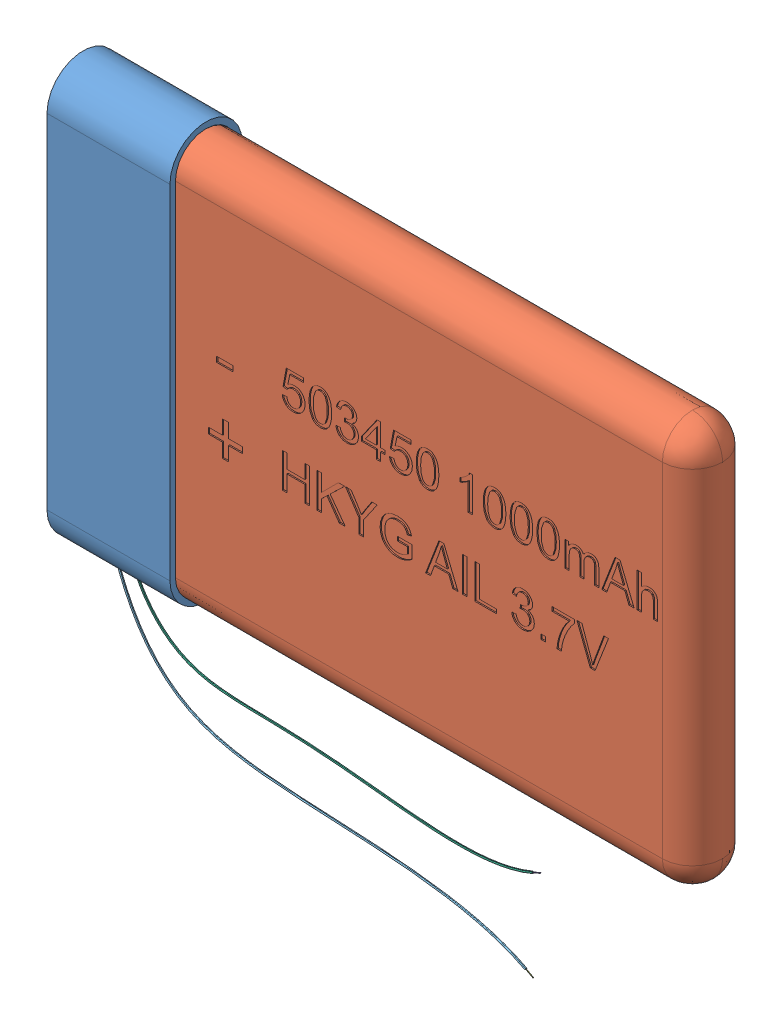
SolidWorks assembly Bateria LiPo 3.7V 1000mA 503450 v23, configuration Predeterminado. Lengths in mm.
Overall size (40.92 46.82 23.16).
9 component instances, 8 part files, 0 mates.
Components (placement in the parent):
- parte de la pila_lipo v4-1: parte de la pila_lipo v4 [Predeterminado] at (-27.4003 0 2.4569) x (0 1 0) z (-1 0 0) size (34.5 6 10.2)
- COMPOUND007-1: COMPOUND007 [Predeterminado] at origin size (40.92 42.22 21.59)
  - COMPOUND-1: COMPOUND [Predeterminado] at origin size (5.9 5.4 4.15)
  - COMPOUND001-1: COMPOUND001 [Predeterminado] at origin size (3 9 0.2)
  - COMPOUND002-1: COMPOUND002 [Predeterminado] at origin size (3 9 0.2)
  - COMPOUND003-1: COMPOUND003 [Predeterminado] at origin size (34.86 31.57 0.38)
  - COMPOUND004-1: COMPOUND004 [Predeterminado] at origin size (34.64 21.24 0.38)
  - COMPOUND005-1: COMPOUND005 [Predeterminado] at origin size (0.64 0.37 0.05)
  - COMPOUND006-1: COMPOUND006 [Predeterminado] at origin size (0.66 0.32 0.05)
